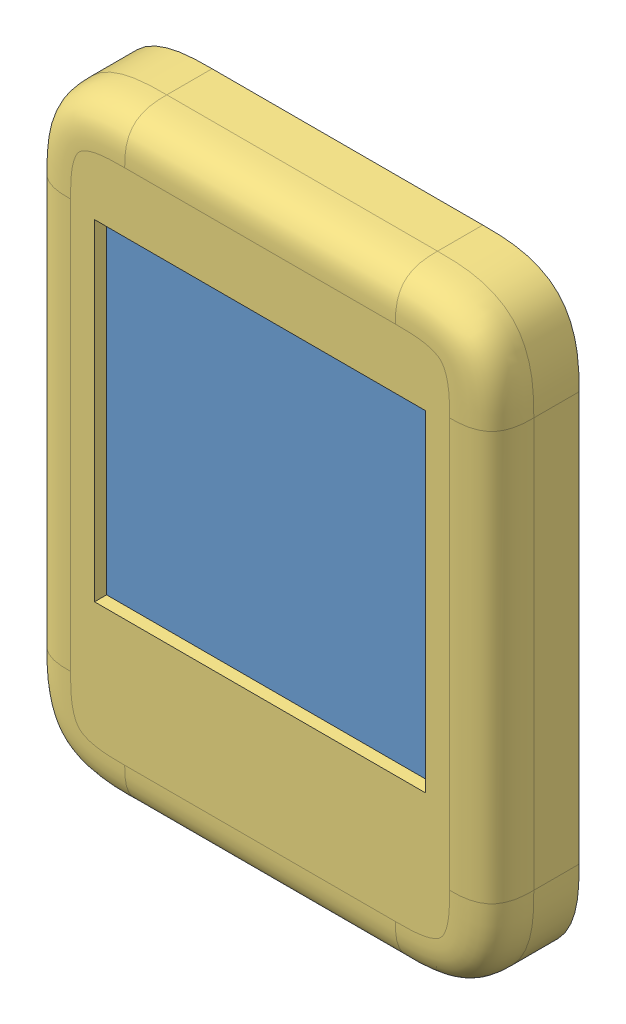
SolidWorks assembly 桌面小屏幕装配体, configuration 默认. Lengths in mm.
Overall size (38.6 50.1 10.81).
5 component instances, 5 part files, 11 mates.
Components (placement in the parent):
- 屏幕-1: 屏幕 [默认] at origin size (31.8 38.22 3.51)
- 桌面小屏幕电路板3D图纸(零件)-1: 桌面小屏幕电路板3D图纸(零件) [默认] at (-127.0003 27.6011 -4.8001) size (34.53 36.97 7.76)
- 小电池-1: 小电池 [默认] at (-16.6074 -17.0466 -17.6322) size (28 34.54 5.7) (hidden)
- 前壳-1: 前壳 [默认] at origin size (38.6 50.1 7.31)
- 压板-1: 压板 [默认] x (-1 0 0) z (0 0 -1) size (35.4 40 1)
Mates (geometry in assembly coordinates):
- 距离1: distance = 3.2 mm anti-aligned: plane of 桌面小屏幕电路板3D图纸(零件)-1 through (-1.788 0 -3.2) normal (0 0 1); plane of 屏幕-1 through (0 0 0) normal (0 0 -1)
- 宽度1: width anti-aligned: plane of 桌面小屏幕电路板3D图纸(零件)-1 through (-8.2004 -5.5624 -1.1799) normal (-1 0 0); plane of 桌面小屏幕电路板3D图纸(零件)-1 through (8.2004 -5.5624 -1.1799) normal (1 0 0); plane of 屏幕-1 through (7.25 -18.66 0.43) normal (1 0 0); plane of 屏幕-1 through (-7.25 -18.66 0.43) normal (-1 0 0)
- 宽度2: width aligned: plane of 屏幕-1 through (15.9 18.66 0.98) normal (0 1 0); plane of 屏幕-1 through (15.9 -18.66 0.98) normal (0 -1 0); plane of 桌面小屏幕电路板3D图纸(零件)-1 through (-15.288 18.4873 -4.8001) normal (0 1 0); plane of 桌面小屏幕电路板3D图纸(零件)-1 through (11.712 -18.4873 -4.8001) normal (0 -1 0)
- 在位1: in place: plane of ? through (0 0 0) normal (0 0 1); moOrthogonalPlaneRef_w of ? through (0 0 0) normal (0 1 0); plane of ? through (0 0 0) normal (1 0 0); unknown of ?
- 重合1: coincident aligned: 
- 重合2: coincident aligned: plane of 前壳-1 through (0 0 0) normal (0 1 0)
- 重合3: coincident anti-aligned: plane of 前壳-1 through (0 0 0) normal (1 0 0)
- 在位2: in place: plane of ? through (0 0 0) normal (0 0 -1); plane of 压板-1 through (0 0 0) normal (0 0 -1); plane of ? through (0 0 0) normal (0 0 -1); plane of 压板-1 through (0 0 0) normal (0 1 0); plane of ? through (0 0 0) normal (0 0 -1); plane of 压板-1 through (0 0 0) normal (-1 0 0); plane of ? through (0 0 0) normal (0 0 -1); unknown of 压板-1
- 重合1: coincident aligned: plane of ?; plane of ?
- 重合2: coincident aligned: moOrthogonalPlaneRef_w of 屏幕-1 through (0 0 0) normal (0 1 0); plane of 零件1^桌面小屏幕装配体-1 through (0 0 0) normal (0 1 0)
- 重合3: coincident anti-aligned: moOrthogonalPlaneRef_w of 屏幕-1 through (0 0 0) normal (1 0 0); plane of 零件1^桌面小屏幕装配体-1 through (0 0 0) normal (-1 0 0)
